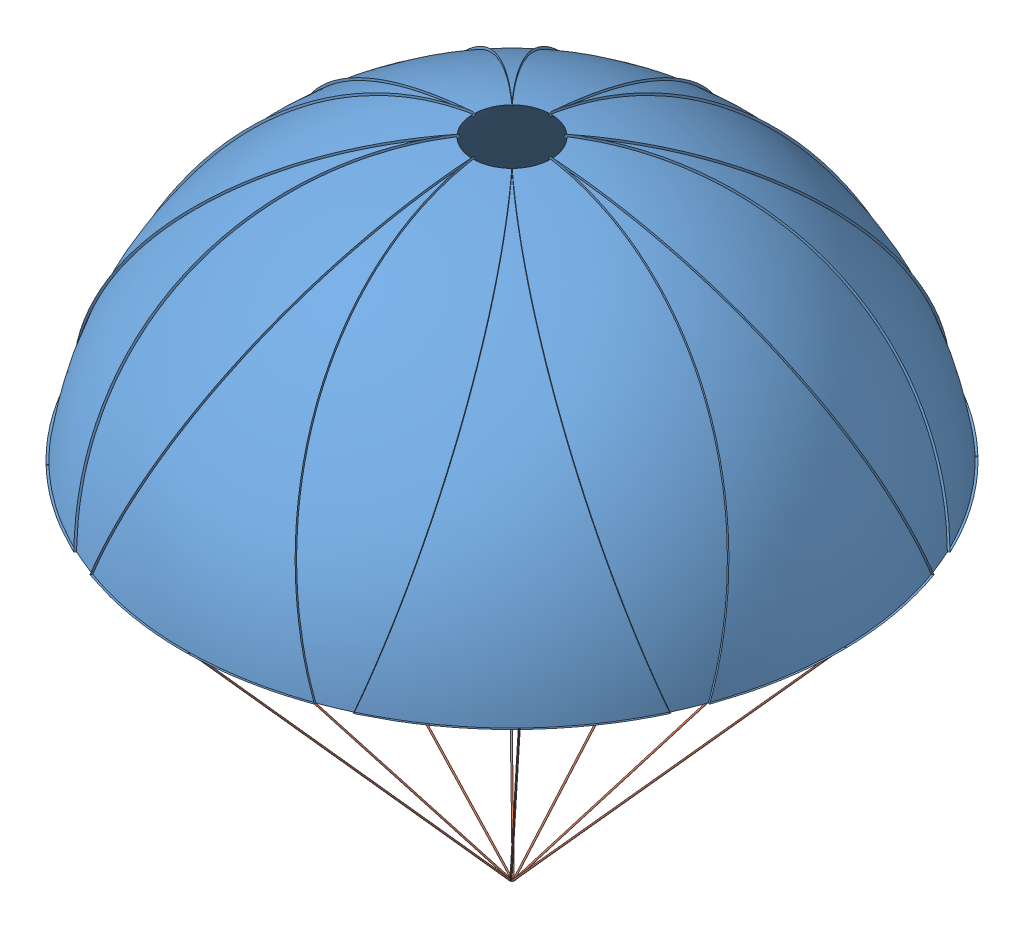
SolidWorks assembly parashute_ass, configuration Default. Lengths in mm.
Overall size (946.53 1283.52 946.53).
9 component instances, 2 part files, 1 mates.
Components (placement in the parent):
- parashute-1: parashute [Default] at (-53.8101 192.378 639.2758) size (946.53 414.48 946.53)
- the rope-8: the rope [Default] at (415.667 261.6831 631.8886) x (-0.673508 0.611226 0.41568) z (-0.667833 -0.74421 0.012246) size (2 2 700)
- the rope-12: the rope [Default] at (283.3838 261.6831 966.0227) x (-0.770172 0.611226 -0.182312) z (-0.480888 -0.74421 -0.46357) size (2 2 700)
- the rope-13: the rope [Default] at (-46.423 261.6831 1108.7528) x (-0.41568 0.611226 -0.673508) z (-0.012246 -0.74421 -0.667833) size (2 2 700)
- the rope-14: the rope [Default] at (-380.557 261.6831 976.4697) x (0.182312 0.611226 -0.770172) z (0.46357 -0.74421 -0.480888) size (2 2 700)
- the rope-15: the rope [Default] at (-523.2872 261.6831 646.6629) x (0.673508 0.611226 -0.41568) z (0.667833 -0.74421 -0.012246) size (2 2 700)
- the rope-16: the rope [Default] at (-391.004 261.6831 312.5288) x (0.770172 0.611226 0.182312) z (0.480888 -0.74421 0.46357) size (2 2 700)
- the rope-17: the rope [Default] at (-61.1972 261.6831 169.7987) x (0.41568 0.611226 0.673508) z (0.012246 -0.74421 0.667833) size (2 2 700)
- the rope-18: the rope [Default] at (272.9368 261.6831 302.0818) x (-0.182312 0.611226 0.770172) z (-0.46357 -0.74421 0.480888) size (2 2 700)
Mates (geometry in assembly coordinates):
- Tangent1: tangent: curve of parashute-1; circle of the rope-8
